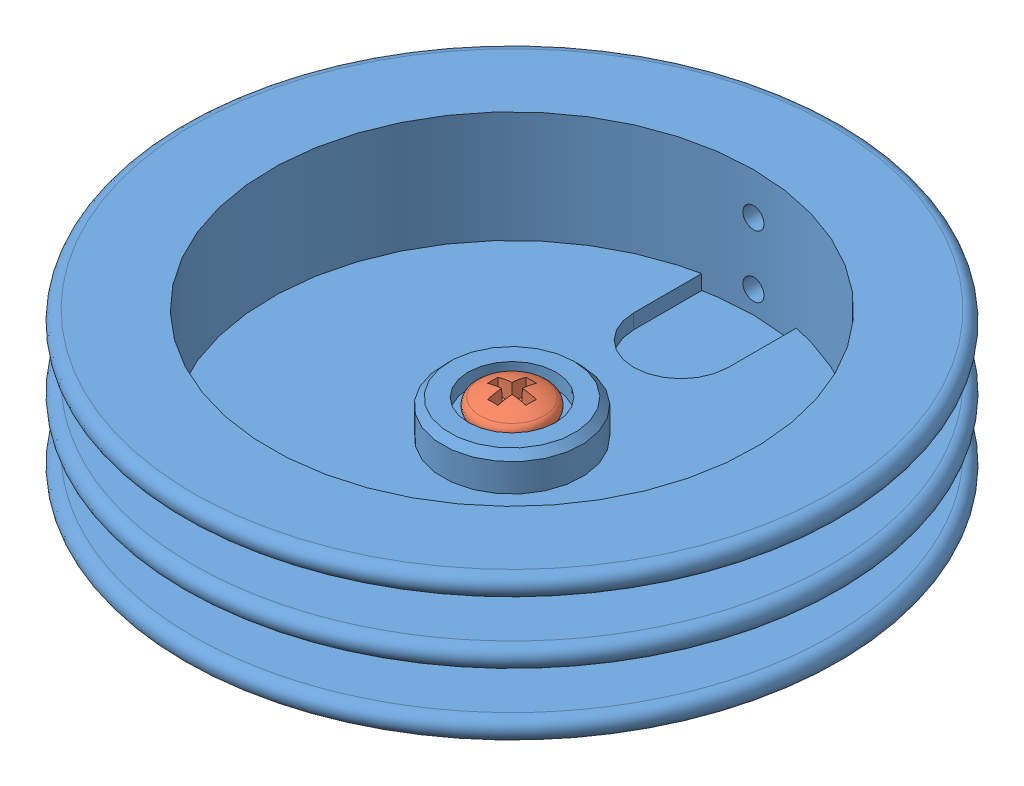
SolidWorks assembly Tetrix Servo Horn Alternate, configuration Default. Lengths in mm.
Overall size (47.8 16.46 47.8).
2 component instances, 2 part files, 0 mates.
Components (placement in the parent):
- Tetrix Servo Horn Alternate Body-1: Tetrix Servo Horn Alternate Body [Default] at origin size (47.8 10.54 47.8)
- Tetrix Servo Horn Alternate Screw-1: Tetrix Servo Horn Alternate Screw [Default] at (0 -5.9182 0) size (5.25 11.58 5.25)
